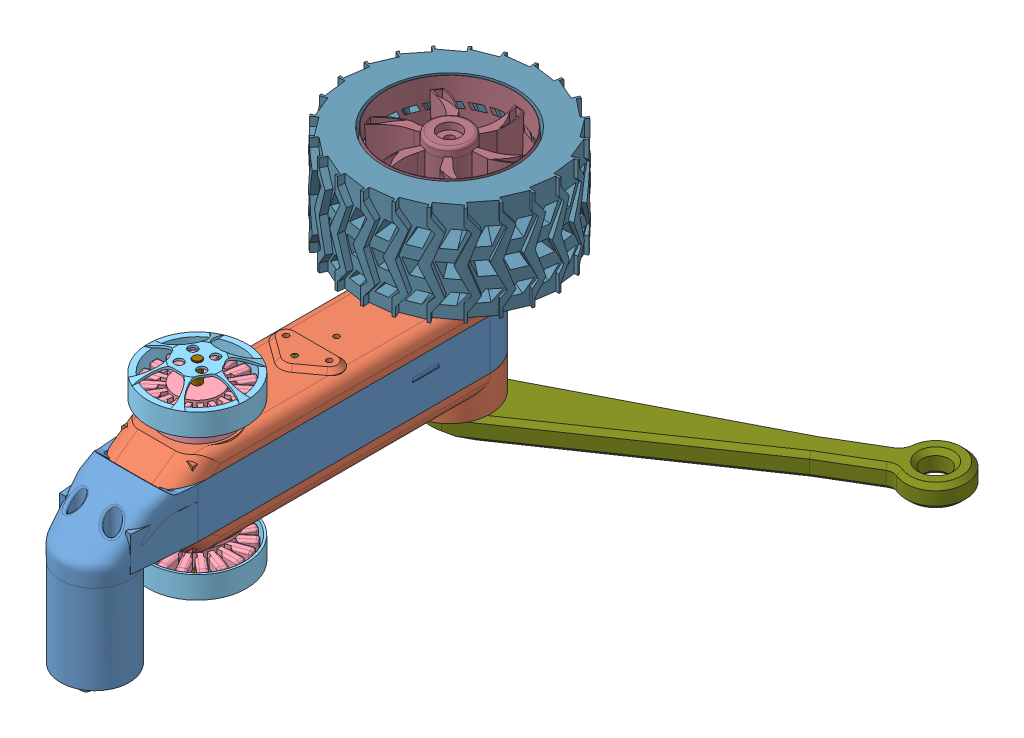
SolidWorks assembly act_core_v3, configuration Default. Lengths in mm.
Overall size (223.45 134.33 275.92).
32 component instances, 16 part files, 54 mates.
Components (placement in the parent):
- upper leg module shell base_v3-1: upper leg module shell base_v3 [Default] at (27.0686 103.6753 170.704) x (-1 0 0) z (0 0 -1) size (37.45 78.01 194.01)
- upper leg module cover_v2_2-1: upper leg module cover_v2_2 [Default] at (27.0686 109.6753 164.3332) x (0 0 1) z (-1 0 0) size (161.8 16.02 37)
- upper leg module cover_v2_2-2: upper leg module cover_v2_2 [Default] at (27.0686 87.1753 164.3332) x (0 0 1) z (1 0 0) size (161.8 16.02 37)
- motor assembly-1: motor assembly [Default] at (27.0686 129.5753 223.504) x (0.534678 0 -0.845056) z (0.845056 0 0.534678) size (16.67 11.86 16.67)
  - motor pulley-1: motor pulley [Default] at (0 -20.1 0) x (1 0 0) z (0 -1 0) size (8.98 9.1 6.7)
  - encoder wheel mount-1: encoder wheel mount [Default] at (0 -28.3 0) x (-0.562764 0 0.826618) z (-0.826618 0 -0.562764) size (12 5.96 12) (hidden)
- T-motor 4004 kv300-1: T-motor 4004 kv300 [Default] at (12.9009 105.545 191.0432) size (60.94 23.74 60.94)
  - motor rotor-1: motor rotor [Default] at (14.1676 19.6303 32.4608) size (40 13.5 39.72)
  - motor stator-1: motor stator [Default] at (14.1676 19.6303 32.4608) x (0.854442 0 0.519546) z (0 1 0) size (44.35 44.35 16.24)
- centre pulley-1: centre pulley [Default] at (39.24 91.3287 156.2358) x (0.712464 0 0.701709) z (-0.701709 0 0.712464) size (30 19 30)
  - transmission pulley centre-1: transmission pulley centre [Default] at (7.726 11.8465 25.1899) size (30 6.8 30)
  - centre pulley-1: centre pulley [Default] at (7.726 25.3465 25.1899) x (0.694658 0 -0.71934) z (0 -1 0) size (8.98 9.1 19)
- bearing 8mm x 3mm x 3mm-1: bearing 8mm x 3mm x 3mm [Default] at (27.0686 102.1753 179.604) x (0.990426 0 -0.138045) z (0 -1 0) size (7.96 7.96 3)
- motor shaft_v3-1: motor shaft_v3 [Default] at (27.0686 140.6753 223.504) x (0.606053 0 -0.795424) z (0 -1 0) size (3.99 3.99 38)
- encoder wheel mount-1: encoder wheel mount [Default] at (27.0686 110.9753 223.504) x (1 0 0) z (0 0 -1) size (12 5.96 12)
- bearing 32x25x4mm-1: bearing 32x25x4mm [Default] at (27.0686 104.1753 109.704) x (0.998143 0 0.060919) z (-0.060919 0 0.998143) size (32 4 32)
- centre pulley-2: centre pulley [Default] at (27.0686 93.6753 179.604) x (-0.512258 0 -0.858832) z (0 -1 0) size (8.98 9.1 19)
- transmission pulley centre-1: transmission pulley centre [Default] at (27.0686 93.1753 179.604) x (0.289271 0 0.957247) z (0.957247 0 -0.289271) size (30 6.8 30)
- motor pulley-1: motor pulley [Default] at (27.0686 93.6753 223.504) x (0.534678 0 -0.845056) z (0 -1 0) size (8.98 9.1 6.7)
- encoder wheel mount-2: encoder wheel mount [Default] at (27.0686 84.6753 223.504) x (0.036347 0 0.999339) z (-0.999339 0 0.036347) size (12 5.96 12)
- transmission pulley output-2: transmission pulley output [Default] at (27.0686 88.1753 109.704) x (0.511916 0 0.859036) z (0.859036 0 -0.511916) size (29 16.4 29)
- motor stator-1: motor stator [Default] at (27.0686 71.6753 223.504) x (0.678657 0 0.734455) z (0 -1 0) size (44.35 44.35 16.24)
- motor rotor-1: motor rotor [Default] at (27.0686 71.6753 223.504) x (1 0 0) z (0 0 -1) size (40 13.5 39.72)
- bearing 32x25x4mm-2: bearing 32x25x4mm [Default] at (27.0686 88.6753 109.704) x (0.98877 0 0.149448) z (-0.149448 0 0.98877) size (32 4 32)
- bearing 8mm x 3mm x 3mm-3: bearing 8mm x 3mm x 3mm [Default] at (27.0686 97.1753 179.604) x (0.918615 0 -0.395154) z (0 -1 0) size (7.96 7.96 3)
- motor shaft_v3-2: motor shaft_v3 [Default] at (27.0686 55.6753 223.504) x (1 0 0) z (0 1 0) size (3.99 3.99 38)
- Wheel assembly-1: Wheel assembly [Default] at (64.2692 108.4345 90.3558) x (-0.906183 0 -0.422886) z (0 1 0) size (127.22 127.22 45)
  - wheel-1: wheel [Default] at (25.5285 33.2647 43.0752) size (60 60 45)
  - tyre-1: tyre [Default] at (25.5285 33.2647 65.5752) x (0 0 -1) z (0.684345 0.729158 0) size (45 90 90)
- transmission pulley output_wheel-1: transmission pulley output_wheel [Default] at (27.0686 108.6753 109.704) x (0.991072 0 0.133328) z (-0.133328 0 0.991072) size (29 16.4 29)
- motor shaft_v3-3: motor shaft_v3 [Default] at (27.0686 115.0074 109.704) x (-0.742983 0 -0.66931) z (0 1 0) size (3.99 3.99 38)
- lower leg-1: lower leg [Default] at (95.7914 61.1653 68.7508) x (0.859036 0 -0.511916) z (0.511916 0 0.859036) size (187 20 27)
Mates (geometry in assembly coordinates):
- Coincident1: coincident aligned: plane of upper leg module shell base_v3-1 through (45.5686 97.6753 130.704) normal (1 0 0); plane of upper leg module cover_v2_2-1 through (45.5686 117.6753 241.7032) normal (1 0 0)
- Coincident2: coincident anti-aligned: plane of upper leg module shell base_v3-1 through (8.5686 109.6753 130.704) normal (0 1 0); plane of upper leg module cover_v2_2-1 through (27.0686 109.6753 164.3332) normal (0 -1 0)
- Concentric1: concentric aligned: cylinder of upper leg module shell base_v3-1 through (27.0686 96.8953 109.704) axis (0 -1 0) radius 18.5018; cylinder of upper leg module cover_v2_2-1 through (27.0686 125.6853 109.704) axis (0 -1 0) radius 18.5018
- Coincident3: coincident anti-aligned: plane of upper leg module shell base_v3-1 through (27.0686 87.1753 109.704) normal (0 -1 0); plane of upper leg module cover_v2_2-2 through (27.0686 87.1753 164.3332) normal (0 1 0)
- Coincident5: coincident aligned: plane of upper leg module shell base_v3-1 through (45.5686 97.6753 130.704) normal (1 0 0); plane of upper leg module cover_v2_2-2 through (45.5686 79.1753 241.7032) normal (1 0 0)
- Concentric3: concentric anti-aligned: cylinder of upper leg module cover_v2_2-1 through (27.0686 113.6753 223.504) axis (0 -1 0) radius 16.1235; cylinder of T-motor 4004 kv300-1/motor rotor-1 through (27.0686 117.6753 223.504) axis (0 1 0) radius 15
- Concentric4: concentric aligned: line of upper leg module cover_v2_2-1 through (39.5686 113.6753 223.504) axis (0 1 0); cylinder of T-motor 4004 kv300-1/motor rotor-1 through (39.5686 117.6753 223.504) axis (0 1 0) radius 2
- Coincident7: coincident anti-aligned: plane of upper leg module cover_v2_2-1 through (27.0686 117.6753 164.3332) normal (0 1 0); plane of T-motor 4004 kv300-1/motor rotor-1 through (27.0686 117.6753 223.504) normal (0 -1 0)
- Concentric5: concentric anti-aligned: cylinder of motor assembly-1/motor shaft-1 through (27.0686 99.9613 223.504) axis (0 1 0) radius 1.995; line of T-motor 4004 kv300-1/motor rotor-1 through (27.0686 131.1753 223.504) axis (0 -1 0)
- Concentric6: concentric anti-aligned: cylinder of upper leg module shell base_v3-1 through (27.0686 101.1753 179.604) axis (0 -1 0) radius 3.98; cylinder of centre pulley-1/centre pulley-1 through (27.0686 100.1753 179.604) axis (0 1 0) radius 1.995
- Concentric7: concentric anti-aligned: cylinder of upper leg module shell base_v3-1 through (27.0686 101.1753 179.604) axis (0 -1 0) radius 3.98; cylinder of bearing 8mm x 3mm x 3mm-1 through (27.0686 99.1753 179.604) axis (0 1 0) radius 3.98
- Coincident12: coincident anti-aligned: plane of upper leg module shell base_v3-1 through (13.5686 99.1753 130.704) normal (0 1 0); plane of bearing 8mm x 3mm x 3mm-1 through (27.0686 99.1753 179.604) normal (0 -1 0)
- Coincident15: coincident anti-aligned: plane of centre pulley-1/centre pulley-1 through (27.0686 102.1753 179.604) normal (0 -1 0); plane of bearing 8mm x 3mm x 3mm-1 through (27.0686 102.1753 179.604) normal (0 1 0)
- Coincident16: coincident aligned: plane of motor assembly-1/motor pulley-1 through (27.0686 109.4753 223.504) normal (0 1 0); plane of centre pulley-1/transmission pulley centre-1 through (27.0686 109.4753 179.604) normal (0 1 0)
- Concentric8: concentric anti-aligned: cylinder of T-motor 4004 kv300-1/motor rotor-1 through (27.0686 130.1753 223.504) axis (0 -1 0) radius 2; cylinder of motor shaft_v3-1 through (27.0686 102.6753 223.504) axis (0 1 0) radius 1.995
- Coincident17: coincident aligned: plane of centre pulley-1/transmission pulley centre-1 through (27.0686 102.6753 179.604) normal (0 -1 0); plane of motor shaft_v3-1 through (27.0686 102.6753 223.504) normal (0 -1 0)
- Concentric9: concentric aligned: cylinder of motor assembly-1/motor pulley-1 through (27.0686 102.7753 223.504) axis (0 1 0) radius 2; cylinder of motor shaft_v3-1 through (27.0686 102.6753 223.504) axis (0 1 0) radius 1.995
- Parallel1: parallel aligned: plane of motor assembly-1/motor pulley-1 through (27.0686 102.7753 223.504) normal (0 -1 0); plane of motor shaft_v3-1 through (27.0686 102.6753 223.504) normal (0 -1 0)
- Concentric10: concentric aligned: cylinder of motor shaft_v3-1 through (27.0686 102.6753 223.504) axis (0 1 0) radius 1.995; cylinder of encoder wheel mount-1 through (27.0686 106.9753 223.504) axis (0 1 0) radius 2
- Coincident19: coincident anti-aligned: plane of motor assembly-1/motor pulley-1 through (27.0686 109.4753 223.504) normal (0 1 0); plane of encoder wheel mount-1 through (27.0686 109.4753 223.504) normal (0 -1 0)
- Concentric11: concentric anti-aligned: cylinder of upper leg module shell base_v3-1 through (27.0686 104.1753 109.704) axis (0 1 0) radius 16; cylinder of bearing 32x25x4mm-1 through (27.0686 108.1753 109.704) axis (0 -1 0) radius 12.5
- Coincident20: coincident anti-aligned: plane of upper leg module shell base_v3-1 through (27.0686 104.1753 109.704) normal (0 1 0); plane of bearing 32x25x4mm-1 through (27.0686 104.1753 109.704) normal (0 -1 0)
- Concentric12: concentric anti-aligned: cylinder of bearing 32x25x4mm-1 through (27.0686 108.1753 109.704) axis (0 -1 0) radius 12.5; cylinder of transmission pulley output-1 through (27.0686 104.3253 109.704) axis (0 1 0) radius 12.575
- Coincident21: coincident anti-aligned: plane of bearing 32x25x4mm-1 through (27.0686 108.1753 109.704) normal (0 1 0); plane of transmission pulley output-1 through (27.0686 108.1753 109.704) normal (0 -1 0)
- Concentric14: concentric anti-aligned: cylinder of upper leg module shell base_v3-1 through (27.0686 88.8753 109.704) axis (0 1 0) radius 16.5; cylinder of bearing 32x25x4mm-2 through (27.0686 92.6753 109.704) axis (0 -1 0) radius 16
- Coincident22: coincident anti-aligned: plane of upper leg module shell base_v3-1 through (27.0686 92.6753 109.704) normal (0 -1 0); circle of bearing 32x25x4mm-2
- Concentric16: concentric aligned: cylinder of transmission pulley output-2 through (27.0686 92.5253 109.704) axis (0 -1 0) radius 12.575; cylinder of bearing 32x25x4mm-2 through (27.0686 92.6753 109.704) axis (0 -1 0) radius 12.5
- Coincident23: coincident anti-aligned: plane of transmission pulley output-2 through (27.0686 88.6753 109.704) normal (0 1 0); plane of bearing 32x25x4mm-2 through (27.0686 88.6753 109.704) normal (0 -1 0)
- Concentric17: concentric aligned: cylinder of upper leg module shell base_v3-1 through (27.0686 96.1753 179.604) axis (0 1 0) radius 3.98; cylinder of bearing 8mm x 3mm x 3mm-3 through (27.0686 94.1753 179.604) axis (0 1 0) radius 3.98
- Coincident25: coincident anti-aligned: plane of upper leg module shell base_v3-1 through (27.0686 97.1753 179.604) normal (0 -1 0); plane of bearing 8mm x 3mm x 3mm-3 through (27.0686 97.1753 179.604) normal (0 1 0)
- Concentric18: concentric anti-aligned: cylinder of centre pulley-2 through (27.0686 96.1753 179.604) axis (0 -1 0) radius 1.995; cylinder of bearing 8mm x 3mm x 3mm-3 through (27.0686 94.1753 179.604) axis (0 1 0) radius 2
- Coincident26: coincident anti-aligned: plane of centre pulley-2 through (27.0686 94.1753 179.604) normal (0 1 0); plane of bearing 8mm x 3mm x 3mm-3 through (27.0686 94.1753 179.604) normal (0 -1 0)
- Coincident27: coincident aligned: plane of centre pulley-2 through (27.0686 93.6753 179.604) normal (0 1 0); plane of transmission pulley centre-1 through (27.0686 93.6753 179.604) normal (0 1 0)
- Concentric19: concentric aligned: circle of centre pulley-2; cylinder of transmission pulley centre-1 through (27.0686 93.6753 179.604) axis (0 -1 0) radius 15
- Coincident28: coincident aligned: cylinder of centre pulley-2 through (27.0686 79.6753 179.604) axis (0 1 0) radius 4.57; circle of transmission pulley centre-1
- Parallel2: parallel anti-aligned: plane of transmission pulley centre-1 through (27.2454 96.8753 175.7377) normal (0.969507 0 0.245065); plane of centre pulley-2 through (26.3162 79.6753 179.4139) normal (-0.969507 0 -0.245065)
- Coincident30: coincident anti-aligned: plane of upper leg module cover_v2_2-2 through (27.0686 79.1753 164.3332) normal (0 -1 0); plane of motor rotor-1 through (27.0686 79.1753 223.504) normal (0 1 0)
- Concentric20: concentric aligned: cylinder of upper leg module cover_v2_2-2 through (14.5686 84.1753 223.504) axis (0 -1 0) radius 1.6; cylinder of motor rotor-1 through (14.5686 79.1753 223.504) axis (0 -1 0) radius 2
- Concentric21: concentric aligned: cylinder of motor stator-1 through (27.0686 61.6753 223.504) axis (0 1 0) radius 22.175; line of motor rotor-1 through (27.0686 65.6753 223.504) axis (0 1 0)
- Concentric22: concentric aligned: cylinder of upper leg module cover_v2_2-2 through (27.0686 84.1753 223.504) axis (0 -1 0) radius 12.5; cylinder of motor rotor-1 through (27.0686 79.1753 223.504) axis (0 -1 0) radius 15
- Coincident33: coincident aligned: plane of motor stator-1 through (27.0686 71.6753 223.504) normal (0 1 0); plane of motor rotor-1 through (27.0686 71.6753 223.504) normal (0 1 0)
- Concentric23: concentric anti-aligned: cylinder of motor rotor-1 through (27.0686 66.6753 223.504) axis (0 1 0) radius 2; cylinder of motor shaft_v3-2 through (27.0686 93.6753 223.504) axis (0 -1 0) radius 1.995
- Coincident34: coincident aligned: plane of transmission pulley centre-1 through (27.0686 93.6753 179.604) normal (0 1 0); plane of motor shaft_v3-2 through (27.0686 93.6753 223.504) normal (0 1 0)
- Concentric24: concentric anti-aligned: cylinder of motor pulley-1 through (27.0686 86.9753 223.504) axis (0 1 0) radius 2; line of motor shaft_v3-2 through (27.0686 93.4753 223.504) axis (0 -1 0)
- Coincident35: coincident aligned: plane of transmission pulley centre-1 through (27.0686 93.6753 179.604) normal (0 1 0); plane of motor pulley-1 through (27.0686 93.6753 223.504) normal (0 1 0)
- Concentric25: concentric aligned: line of upper leg module cover_v2_2-2 through (27.0686 83.1753 223.504) axis (0 -1 0); cylinder of encoder wheel mount-2 through (27.0686 88.6753 223.504) axis (0 -1 0) radius 2
- Coincident36: coincident anti-aligned: plane of motor pulley-1 through (27.0686 86.9753 223.504) normal (0 -1 0); plane of encoder wheel mount-2 through (27.0686 86.9753 223.504) normal (0 1 0)
- Concentric26: concentric anti-aligned: cylinder of bearing 32x25x4mm-1 through (27.0686 108.1753 109.704) axis (0 -1 0) radius 12.5; cylinder of transmission pulley output_wheel-1 through (27.0686 104.3253 109.704) axis (0 1 0) radius 12.575
- Coincident37: coincident anti-aligned: plane of bearing 32x25x4mm-1 through (27.0686 108.1753 109.704) normal (0 1 0); plane of transmission pulley output_wheel-1 through (27.0686 108.1753 109.704) normal (0 -1 0)
- Concentric27: concentric aligned: cylinder of motor shaft_v3-3 through (27.0686 153.0074 109.704) axis (0 -1 0) radius 1.995; cylinder of transmission pulley output_wheel-1 through (27.0686 143.4713 109.704) axis (0 -1 0) radius 1.995
- Concentric28: concentric anti-aligned: cylinder of Wheel assembly-1/wheel-1 through (27.0686 133.5097 109.704) axis (0 1 0) radius 1.9949; cylinder of motor shaft_v3-3 through (27.0686 153.0074 109.704) axis (0 -1 0) radius 1.995
- Coincident38: coincident anti-aligned: plane of transmission pulley output-2 through (37.3595 92.5253 109.392) normal (-0.511916 0 -0.859036); plane of lower leg-1 through (23.1854 81.1653 117.8386) normal (0.511916 0 0.859036)
- Coincident39: coincident anti-aligned: plane of transmission pulley output-2 through (21.8968 92.5253 118.6065) normal (0.859036 0 -0.511916); plane of lower leg-1 through (21.1289 81.1653 117.3179) normal (-0.859036 0 0.511916)
- Coincident40: coincident anti-aligned: plane of upper leg module cover_v2_2-2 through (27.0686 71.1653 109.704) normal (0 -1 0); plane of lower leg-1 through (157.3676 71.1653 44.8614) normal (0 1 0)
